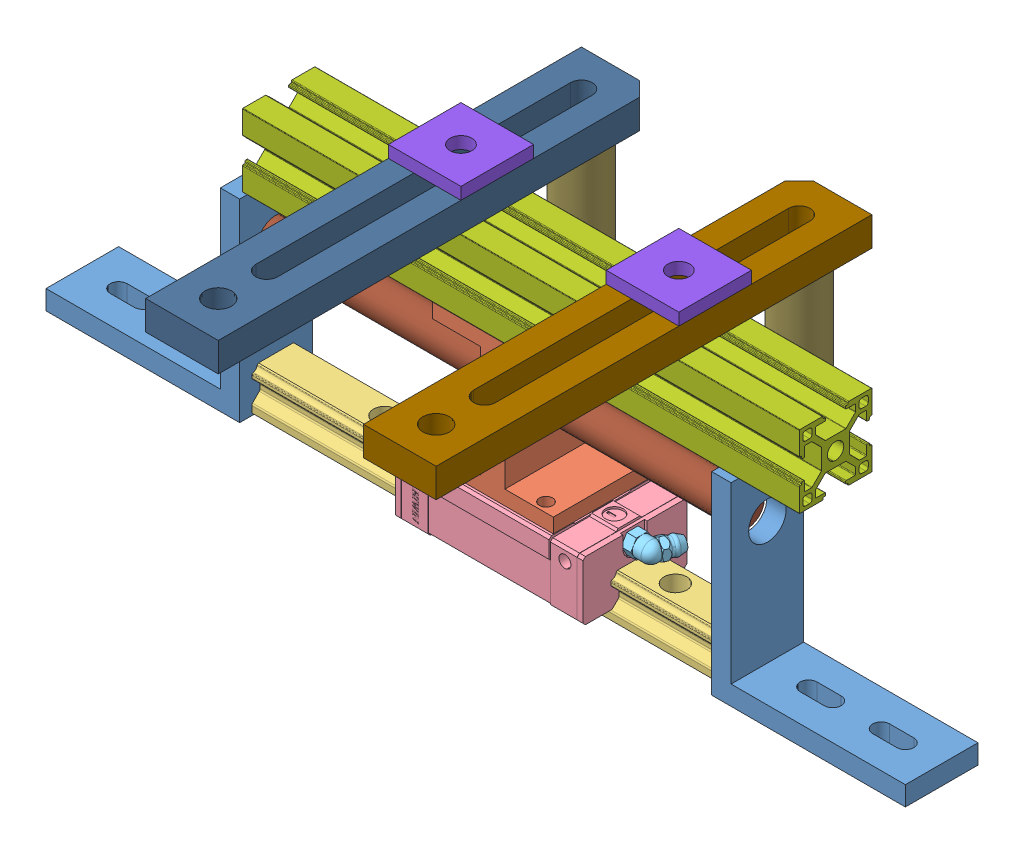
SolidWorks assembly 丝杆调整顶料, configuration 默认. Lengths in mm.
Overall size (355 135 180).
17 component instances, 12 part files, 22 mates.
Components (placement in the parent):
- 丝杆-L型块-1: 丝杆-L型块 [默认] at origin size (80 80 30)
- 丝杆-I型块-1: 丝杆-I型块 [默认] at (-85.4378 59 -5) size (56.44 58 40)
- HGR20 导轨195-1: HGR20 导轨195 [默认] at (-29.95 7.3473 15.526) x (0 0 -1) z (1 0 0) size (20 17.5 195)
- HGR20 滑块-1: HGR20 滑块 [默认] at (-327.4378 17.5 15) x (-1 0 0) z (0 0 -1) size (97.48 36.05 44)
  - LM滑块-1: LM滑块 [默认] at (-242 0 0) x (0 0 -1) z (1 0 0) size (44 25.4 77.5)
  - 螺纹接头-1: 螺纹接头 [默认] at (-295.1321 19.3089 7.0344) x (-0.46194 0.191342 -0.866025) z (-0.745248 -0.613137 0.262049) size (15.11 19.64 23.4)
  - M6H-1: M6H [默认] at (-205.2216 7.1862 0) x (0 1 0) z (1 0 0) size (8 8 8)
- 丝杆-L型块-2: 丝杆-L型块 [默认] at (-195 0 30) x (-1 0 0) z (0 0 -1) size (80 80 30)
- 顶料连接-1: 顶料连接 [默认] at (-30.353 732.3442 1239.9537) x (0 -1 0) z (1 0 0) size (47 180 230)
  - 铝型材230-2: 铝型材230 [默认<按加工>] at (629.3442 1219.9537 -158.4794) x (0 0 1) z (0 1 0) size (230 30 30)
  - 连接块30x5-1: 连接块30x5 [默认] at (597.3442 1220.2037 -83.4794) x (0 1 0) z (1 0 0) size (30 30 5)
  - 顶料块尼龙-1: 顶料块尼龙 [默认] at (602.3442 1194.9537 6.5206) x (0 0 -1) z (1 0 0) size (30 180 12)
  - 连接块30x5-2: 连接块30x5 [默认] at (597.3442 1220.2037 6.5206) x (0 1 0) z (1 0 0) size (30 30 5)
  - 顶料块尼龙1-1: 顶料块尼龙1 [默认] at (602.3442 1194.9537 -83.4794) x (0 0 -1) z (1 0 0) size (30 180 12)
- 丝杆200-1: 丝杆200 [默认] at (-200.2665 59 15) x (0 0.51254 0.858663) z (-1 0 0) size (14 14 200)
- 圆柱顶料头-1: 圆柱顶料头 [默认] at (-113.8324 70 -30) size (20 48 20)
- 圆柱顶料头-2: 圆柱顶料头 [默认] at (-23.8324 70 -30) size (20 48 20)
Mates (geometry in assembly coordinates):
- 重合1: coincident anti-aligned: plane of HGR20 导轨195-1 through (0 17.5 22.2307) normal (0 1 0); plane of HGR20 滑块-1/LM滑块-1 through (-60.1878 17.5 7.7693) normal (0 -1 0)
- 重合2: coincident anti-aligned: plane of HGR20 导轨195-1 through (0 13.4664 25) normal (0 0 1); plane of HGR20 滑块-1/LM滑块-1 through (-60.1878 14.5236 25) normal (0 0 -1)
- LimitDistance2: limit distance = 46.6878 mm aligned: plane of HGR20 滑块-1/LM滑块-1 through (-46.6878 17.3251 14.9769) normal (1 0 0); plane of HGR20 导轨195-1 through (0 8.2815 15.0001) normal (1 0 0)
- 重合5: coincident anti-aligned: plane of 零件7^丝杆调整顶料-1 through (0 80 30) normal (-1 0 0); plane of HGR20 导轨195-1 through (0 8.2815 15.0001) normal (1 0 0)
- 重合8: coincident aligned: plane of 零件7^丝杆调整顶料-1 through (0 0 30) normal (0 -1 0); plane of HGR20 导轨195-1 through (0 0 6) normal (0 -1 0)
- 重合12: coincident anti-aligned: plane of 零件1^丝杆调整顶料-1 through (-110.4378 30 35) normal (0 -1 0); plane of HGR20 滑块-1/LM滑块-1 through (-60.1878 30 3) normal (0 1 0)
- 同心1: concentric anti-aligned: cylinder of 零件1^丝杆调整顶料-1 through (-67.4378 30 -1) axis (0 -1 0) radius 2.75; cylinder of HGR20 滑块-1/LM滑块-1 through (-67.4378 27 -1) axis (0 1 0) radius 2.067
- 重合13: coincident aligned: plane of 零件7^丝杆调整顶料-1 through (0 0 30) normal (0 0 1); plane of 零件7^丝杆调整顶料-2 through (-195 0 30) normal (0 0 1)
- 重合14: coincident anti-aligned: plane of HGR20 导轨195-1 through (-195 -12.5 113.009) normal (-1 0 0); plane of 零件7^丝杆调整顶料-2 through (-195 80 0) normal (1 0 0)
- 重合15: coincident aligned: plane of 零件7^丝杆调整顶料-1 through (0 0 30) normal (0 -1 0); plane of 零件7^丝杆调整顶料-2 through (-195 0 0) normal (0 -1 0)
- 重合16: coincident anti-aligned: plane of 丝杆-I型块^丝杆调整顶料-1 through (-110.4378 88 35) normal (0 1 0); plane of 顶料连接-1/铝型材230-2 through (41.1676 88 14.5) normal (0 -1 0)
- 重合17: coincident aligned: plane of 丝杆-I型块^丝杆调整顶料-1 through (-85.4378 59 35) normal (0 0 1); plane of 顶料连接-1/铝型材230-2 through (41.1676 97.5 35) normal (0 0 1)
- 距离3: distance = 5 mm aligned: plane of HGR20 导轨195-1 through (0 1 25) normal (0 0 1); plane of 丝杆-L型块^丝杆调整顶料-2 through (-195 0 30) normal (0 0 1)
- 同心2: concentric anti-aligned: cylinder of 丝杆-I型块^丝杆调整顶料-1 through (-103.4378 30 31) axis (0 -1 0) radius 2.75; cylinder of HGR20 滑块-1/LM滑块-1 through (-103.4378 27 31) axis (0 1 0) radius 2.067
- 同心3: concentric anti-aligned: cylinder of 丝杆-I型块^丝杆调整顶料-1 through (-67.4378 30 31) axis (0 -1 0) radius 2.75; cylinder of HGR20 滑块-1/LM滑块-1 through (-67.4378 27 31) axis (0 1 0) radius 2.067
- 同心4: concentric anti-aligned: cylinder of 丝杆-L型块-2 through (-195 59 15) axis (1 0 0) radius 7.75; cylinder of 丝杆200-1 through (-200.2665 59 15) axis (-1 0 0) radius 7
- 平行2: parallel anti-aligned: cylinder of 顶料连接-1/顶料块尼龙1-1 through (-113.8324 130 -30) axis (0 -1 0) radius 4.5; cylinder of 圆柱顶料头-1 through (-113.8324 118 -30) axis (0 1 0) radius 2.5
- 平行3: parallel anti-aligned: plane of 顶料连接-1/顶料块尼龙1-1 through (-113.8324 118 45) normal (0 -1 0); plane of 圆柱顶料头-1 through (-113.8324 118 -30) normal (0 1 0)
- 同心7: concentric anti-aligned: cylinder of 顶料连接-1/顶料块尼龙1-1 through (-113.8324 130 -30) axis (0 -1 0) radius 4.5; cylinder of 圆柱顶料头-1 through (-113.8324 118 -30) axis (0 1 0) radius 2.5
- 重合22: coincident anti-aligned: plane of 顶料连接-1/顶料块尼龙1-1 through (-113.8324 118 45) normal (0 -1 0); plane of 圆柱顶料头-1 through (-113.8324 118 -30) normal (0 1 0)
- 同心8: concentric anti-aligned: cylinder of 顶料连接-1/顶料块尼龙-1 through (-23.8324 130 -30) axis (0 -1 0) radius 4.5; cylinder of 圆柱顶料头-2 through (-23.8324 118 -30) axis (0 1 0) radius 2.5
- 重合23: coincident anti-aligned: plane of 顶料连接-1/顶料块尼龙-1 through (-23.8324 118 45) normal (0 -1 0); plane of 圆柱顶料头-2 through (-23.8324 118 -30) normal (0 1 0)
